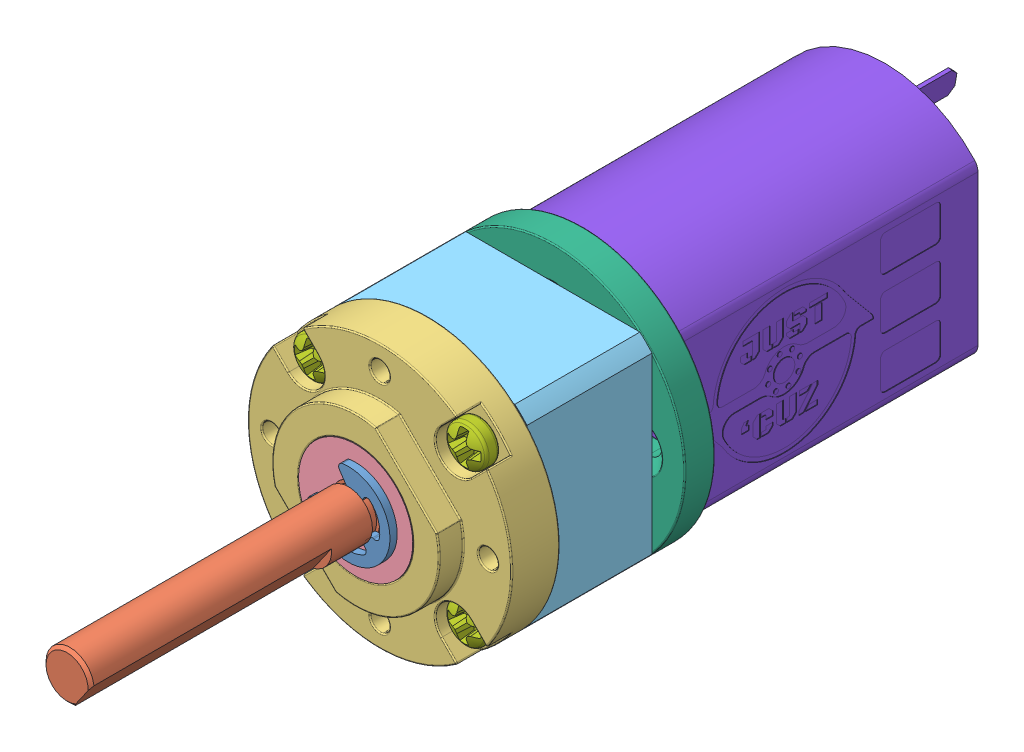
SolidWorks assembly DartBox V2 4mm Shaft, configuration Default. Lengths in mm.
Overall size (21.95 21.95 72.3).
16 component instances, 8 part files, 0 mates.
Components (placement in the parent):
- DartBox+V2+Drive+-+Just+'Cuz+Robotics.stp-1: DartBox+V2+Drive+-+Just+'Cuz+Robotics.stp [Default] at origin size (21.95 21.95 72.3)
  - DartBox V2 Drive Gearbox.stp-1: DartBox V2 Drive Gearbox.stp [Default] at (0.1107 15.4459 54.2565) x (0 1 0) z (0 0 1) size (21.95 21.95 42.9)
    - Ring Gear.stp-1: Ring Gear.stp [Default] at (-10.1305 0.1259 -54.0061) x (0 -1 0) z (0 0 1) size (21.95 21.95 40.4)
      - Front Plate.stp-1: Front Plate.stp [Default] at (0.1259 10.1305 56.5061) x (0 1 0) z (1 0 0) size (21.95 30.5 21.95)
        - Shaft.stp-1: Shaft.stp [Default] x (-0.819152 0 -0.573576) z (0.573576 0 -0.819152) size (6.9 30.3 5.94)
          - 98543A103_Side-Mount External Retaining Rings.stp-1: 98543A103_Side-Mount External Retaining Rings.stp [Default] at (0 16.7 0) x (0 1 0) z (0 0 1) size (0.6 6.9 5.94)
          - Shaft-0.stp-1: Shaft-0.stp [Default] at origin size (4 30.3 4)
        - Front Plate-1.stp-1: Front Plate-1.stp [Default] at origin size (21.95 6.5 21.95)
        - Front Plate-2.stp-1: Front Plate-2.stp [Default] at origin size (9.5 6 9.5)
      - Ring Gear Body.stp-1: Ring Gear Body.stp [Default] at (0.1259 10.1305 56.5061) x (0 1 0) z (1 0 0) size (16.5 10.4 16.5)
    - Motor Mount Plate.stp-1: Motor Mount Plate.stp [Default] at (0 0 2.5) x (1 0 0) z (0 -1 0) size (21.95 3.5 21.95)
    - Screws M2 x 14mm.stp-1: Screws M2 x 14mm.stp [Default] at (6.364 6.364 0.9) size (3.4 3.4 15.61)
    - Screws M2 x 14mm.stp-2: Screws M2 x 14mm.stp [Default] at (-6.364 6.364 0.9) x (0 1 0) z (0 0 1) size (3.4 3.4 15.61)
    - Screws M2 x 14mm.stp-3: Screws M2 x 14mm.stp [Default] at (-6.364 -6.364 0.9) x (-1 0 0) z (0 0 1) size (3.4 3.4 15.61)
    - Screws M2 x 14mm.stp-4: Screws M2 x 14mm.stp [Default] at (6.364 -6.364 0.9) x (0 -1 0) z (0 0 1) size (3.4 3.4 15.61)
  - DartBox 130 motor.stp-1: DartBox 130 motor.stp [Default] at (0.1107 15.4459 54.2565) x (1 0 0) z (0 0 -1) size (15.5 20.4 34.9)
